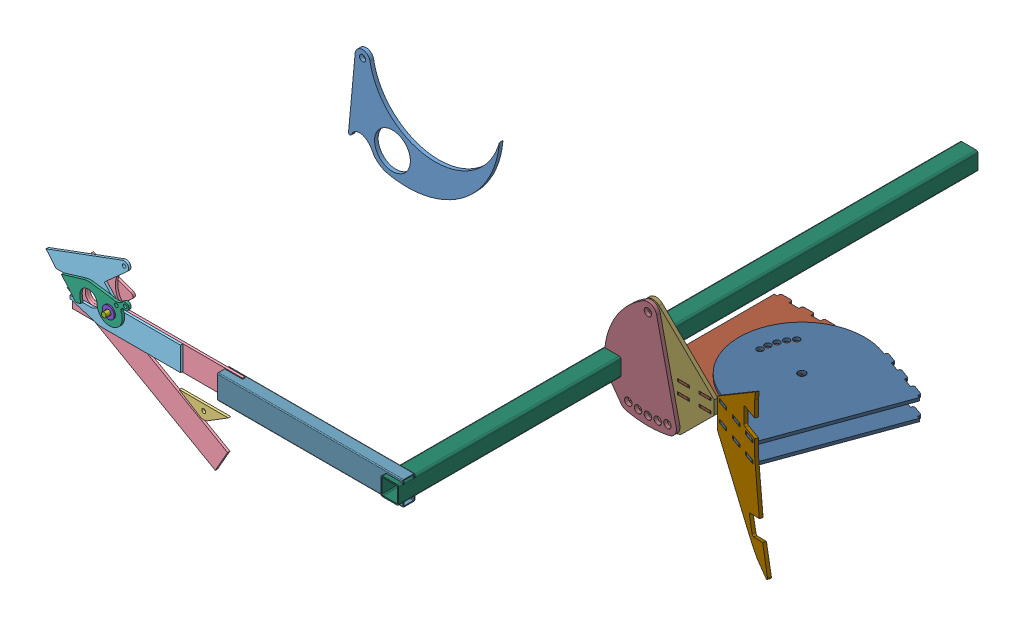
SolidWorks assembly Механизм подъема, configuration 00. Lengths in mm.
Overall size (2570.87 437.97 1423.53).
125 component instances, 32 part files, 102 mates.
Components (placement in the parent):
- Вилка-1: Вилка [--] at (-100 153.8415 0) size (225.09 67 8) (hidden)
- Собачка-1: Собачка [--] at (-64.5 153.8415 -8) size (115.18 50.5 4) (hidden)
- ТП.016.03.05.01 - Ложемент бок (4мм)-1: ТП.016.03.05.01 - Ложемент бок (4мм) [--] at (-100 153.8415 -12) size (285 93.38 4) (hidden)
- ТП.016.03.05.02 - Ложемент низ (4мм)-1: ТП.016.03.05.02 - Ложемент низ (4мм) [--] at (150 118.8415 -16) size (285 4 44) (hidden)
- ТП.016.03.06.01 - Труба связка-1: ТП.016.03.06.01 - Труба связка [--] at (-100 114.8415 28) size (21.3 21.3 971.2) (hidden)
- Модель подъема-1: Модель подъема [--] at (-100 178.8415 -441.6) size (479.74 429.14 0) (hidden)
- ТП.016.03.01.01 - Зуб подъемника (6мм)-1: ТП.016.03.01.01 - Зуб подъемника (6мм) [--] at (-45 169.6674 -441.6) x (0.869959 0.493123 0) z (0 0 1) size (274.94 199.54 6)
- Подшипник ГОСТ 8338-75 -2: Подшипник ГОСТ 8338-75  [Подшипник 205 ГОСТ 8338-75] at (-45 169.6674 -449.1) x (0 0 1) z (-0.017314 -0.99985 0) size (15 52 52) (hidden)
- ТП.016.03.01.02 - Ступица подъема-1: ТП.016.03.01.02 - Ступица подъема [--] at (-45 169.6674 -461.6) x (-1 0 0) z (0 0 -1) size (60 60 40) (hidden)
- ТП.016.03.02 - Ось подъема-1: ТП.016.03.02 - Ось подъема [--] at (-45 169.6674 -461.6) x (-1 0 0) z (0 0 -1) size (25 25 86) (hidden)
- ТП.016.03.03 - Стакан оси подъема-1: ТП.016.03.03 - Стакан оси подъема [--] at (-45 169.6674 -441.6) size (40 40 28) (hidden)
- ТП.016.03.03 - Стакан оси подъема-2: ТП.016.03.03 - Стакан оси подъема [--] at (-45 169.6674 -481.6) x (-1 0 0) z (0 0 -1) size (40 40 28) (hidden)
- ТП.016.03.01.01 - Зуб подъемника (6мм)-2: ТП.016.03.01.01 - Зуб подъемника (6мм) [--] at (-45 169.6674 -475.6) x (0.869959 0.493123 0) z (0 0 1) size (274.94 199.54 6) (hidden)
- Подшипник ГОСТ 8338-75 -3: Подшипник ГОСТ 8338-75  [Подшипник 205 ГОСТ 8338-75] at (-45 169.6674 -474.1) x (0 0 -1) z (0.017314 0.99985 0) size (15 52 52) (hidden)
- ТП.016.03.05.03 - Хомут связки (4мм)-1: ТП.016.03.05.03 - Хомут связки (4мм) [--] at (150 114.8415 -16) size (82.5 38.3 4)
- ТП.016.03.05.04 - Шайба связки (4мм)-1: ТП.016.03.05.04 - Шайба связки (4мм) [--] at (150 114.8415 28) size (82.5 23.3 4)
- ТП.016.03.05.01(01) - Ложемент бок (4мм)-1: ТП.016.03.05.01(01) - Ложемент бок (4мм) [--] at (-100 153.8415 4) size (285 93.13 4)
- ТП.016.03.05.01(01) - Ложемент бок (4мм)-2: ТП.016.03.05.01(01) - Ложемент бок (4мм) [--] at (-100 153.8415 0) x (0.869683 -0.49361 0) z (0 0 1) size (285 93.13 4)
- ТП.016.10.01.01.02.02.01 - Вилка навески (Ст3 S4мм)-1: ТП.016.10.01.01.02.02.01 - Вилка навески (Ст3 S4мм) [ЛАЗЕР] at (-100 153.8415 4) size (225.09 114.93 4)
- ТП.016.10.03.01 - Собачка навески (Ст3 S-4мм)-1: ТП.016.10.03.01 - Собачка навески (Ст3 S-4мм) [На лазер] at (-64.5 153.8415 8) size (112.78 47.58 4)
- ТП.016.10.01.01.02.02.02 - Ось вилки навески-1: ТП.016.10.01.01.02.02.02 - Ось вилки навески [--] at (-64.5 153.8415 4) size (12 12 18)
- ТП.016.10.02 - Втулка собачки навески-1: ТП.016.10.02 - Втулка собачки навески [--] at (-64.5 153.8415 12) size (20 20 6.5)
- ТП.016.11.02.00 - Отвал в сборе-1: ТП.016.11.02.00 - Отвал в сборе [00] at (826.1753 189.0389 -461.6) size (277.03 437.97 1410) (hidden)
  - ТП.016.11.02.01 - Полотно отвала (Ст3 S-2мм)-1: ТП.016.11.02.01 - Полотно отвала (Ст3 S-2мм) [--] at origin size (68.17 399.04 1400)
  - ТП.016.11.02.02 - Продольная труба-1: ТП.016.11.02.02 - Продольная труба [--] at origin size (30 30 1400)
  - ТП.016.11.02.02 - Продольная труба-2: ТП.016.11.02.02 - Продольная труба [--] at (-7.8024 -145.4172 0) x (-0.951057 -0.309017 0) z (0 0 1) size (30 30 1400)
  - ТП.016.11.02.03 - Ребро жесткости отвала (Ст3 S-2мм)-1: ТП.016.11.02.03 - Ребро жесткости отвала (Ст3 S-2мм) [--] at (0 0 675) size (117.05 393.58 2)
  - ТП.016.11.02.03 - Ребро жесткости отвала (Ст3 S-2мм)-2: ТП.016.11.02.03 - Ребро жесткости отвала (Ст3 S-2мм) [--] at (0 0 373) size (117.05 393.58 2)
  - ТП.016.11.02.03 - Ребро жесткости отвала (Ст3 S-2мм)-3: ТП.016.11.02.03 - Ребро жесткости отвала (Ст3 S-2мм) [--] at (0 0 -371) size (117.05 393.58 2)
  - ТП.016.11.02.03 - Ребро жесткости отвала (Ст3 S-2мм)-4: ТП.016.11.02.03 - Ребро жесткости отвала (Ст3 S-2мм) [--] at (0 0 -673) size (117.05 393.58 2)
  - ТП.016.11.02.04.00 - Кронштейн силовой-1: ТП.016.11.02.04.00 - Кронштейн силовой [00] at (-102.2517 -49.6474 0) size (244.94 251.23 220)
    - ТП.016.11.02.04.01 - Цапфа отвала (Ст3 S-5мм)-1: ТП.016.11.02.04.01 - Цапфа отвала (Ст3 S-5мм) [--] at origin size (208.66 5 220)
    - ТП.016.11.02.04.02 - Ребро силовое (Ст3 S-5мм)-1: ТП.016.11.02.04.02 - Ребро силовое (Ст3 S-5мм) [--] at (105.2 0.2 105) size (139.74 251.23 5)
    - ТП.016.11.02.04.02 - Ребро силовое (Ст3 S-5мм)-2: ТП.016.11.02.04.02 - Ребро силовое (Ст3 S-5мм) [--] at (105.2 0.2 -110) size (139.74 251.23 5)
    - ТП.016.11.02.04.01 - Цапфа отвала (Ст3 S-5мм)-2: ТП.016.11.02.04.01 - Цапфа отвала (Ст3 S-5мм) [--] at (0 25.4 0) x (1 0 0) z (0 0 -1) size (208.66 5 220)
  - ТП.016.11.02.05 - Юбка-1: ТП.016.11.02.05 - Юбка [--] at (37.9014 -187.7385 0) x (0.309017 -0.951057 0) z (0 0 1) size (85 8 1410)
  - Болты с шестигранной головкой кт.В (ГОСТ 7798-70)-1: Болты с шестигранной головкой кт.В (ГОСТ 7798-70) [Болт М6-6gx20(S10) ГОСТ 7798-77] at (42.4178 -175.75 690) x (-0.951057 -0.309017 0) z (-0.032305 0.099423 -0.994521) size (24 10.9 10)
  - Шайбы (ГОСТ 11371-78)-1: Шайбы (ГОСТ 11371-78) [Шайба 6 ГОСТ 11371-78] at (32.1464 -179.0874 690) x (0.951057 0.309017 0) z (0.304733 -0.937871 -0.165941) size (1.6 12 12)
  - Гайка (ГОСТ ISO 4032-2014)-1: Гайка (ГОСТ ISO 4032-2014) [Гайка М6 (ГОСТ ISO 4032)] at (28.9128 -180.1381 690) x (0.080366 -0.247341 0.96559) z (0.951057 0.309017 0) size (10 11.05 5.2)
  - Гайка (ГОСТ ISO 4032-2014)-2: Гайка (ГОСТ ISO 4032-2014) [Гайка М6 (ГОСТ ISO 4032)] at (28.9128 -180.1381 552) x (0.14073 -0.433124 0.89028) z (0.951057 0.309017 0) size (10 11.05 5.2)
  - Болты с шестигранной головкой кт.В (ГОСТ 7798-70)-2: Болты с шестигранной головкой кт.В (ГОСТ 7798-70) [Болт М6-6gx20(S10) ГОСТ 7798-77] at (42.4178 -175.75 552) x (-0.951057 -0.309017 0) z (-0.095584 0.294177 -0.950959) size (24 10.9 10)
  - Шайбы (ГОСТ 11371-78)-2: Шайбы (ГОСТ 11371-78) [Шайба 6 ГОСТ 11371-78] at (32.1464 -179.0874 552) x (0.951057 0.309017 0) z (0.287378 -0.884458 -0.367626) size (1.6 12 12)
  - Гайка (ГОСТ ISO 4032-2014)-3: Гайка (ГОСТ ISO 4032-2014) [Гайка М6 (ГОСТ ISO 4032)] at (28.9128 -180.1381 414) x (0.189473 -0.583138 0.789968) z (0.951057 0.309017 0) size (10 11.05 5.2)
  - Болты с шестигранной головкой кт.В (ГОСТ 7798-70)-3: Болты с шестигранной головкой кт.В (ГОСТ 7798-70) [Болт М6-6gx20(S10) ГОСТ 7798-77] at (42.4178 -175.75 414) x (-0.951057 -0.309017 0) z (-0.148605 0.45736 -0.876777) size (24 10.9 10)
  - Шайбы (ГОСТ 11371-78)-3: Шайбы (ГОСТ 11371-78) [Шайба 6 ГОСТ 11371-78] at (32.1464 -179.0874 414) x (0.951057 0.309017 0) z (0.261214 -0.803934 -0.534282) size (1.6 12 12)
  - Гайка (ГОСТ ISO 4032-2014)-4: Гайка (ГОСТ ISO 4032-2014) [Гайка М6 (ГОСТ ISO 4032)] at (28.9128 -180.1381 276) x (0.225997 -0.695549 0.68201) z (0.951057 0.309017 0) size (10 11.05 5.2)
  - Болты с шестигранной головкой кт.В (ГОСТ 7798-70)-4: Болты с шестигранной головкой кт.В (ГОСТ 7798-70) [Болт М6-6gx20(S10) ГОСТ 7798-77] at (42.4178 -175.75 276) x (-0.951057 -0.309017 0) z (-0.189933 0.584555 -0.78881) size (24 10.9 10)
  - Шайбы (ГОСТ 11371-78)-4: Шайбы (ГОСТ 11371-78) [Шайба 6 ГОСТ 11371-78] at (32.1464 -179.0874 276) x (0.951057 0.309017 0) z (0.231523 -0.712554 -0.662318) size (1.6 12 12)
  - Гайка (ГОСТ ISO 4032-2014)-5: Гайка (ГОСТ ISO 4032-2014) [Гайка М6 (ГОСТ ISO 4032)] at (28.9128 -180.1381 138) x (0.250965 -0.77239 0.583464) z (0.951057 0.309017 0) size (10 11.05 5.2)
  - Болты с шестигранной головкой кт.В (ГОСТ 7798-70)-5: Болты с шестигранной головкой кт.В (ГОСТ 7798-70) [Болт М6-6gx20(S10) ГОСТ 7798-77] at (42.4178 -175.75 138) x (-0.951057 -0.309017 0) z (-0.219391 0.675215 -0.704239) size (24 10.9 10)
  - Шайбы (ГОСТ 11371-78)-5: Шайбы (ГОСТ 11371-78) [Шайба 6 ГОСТ 11371-78] at (32.1464 -179.0874 138) x (0.951057 0.309017 0) z (0.203614 -0.626661 -0.752222) size (1.6 12 12)
  - Гайка (ГОСТ ISO 4032-2014)-6: Гайка (ГОСТ ISO 4032-2014) [Гайка М6 (ГОСТ ISO 4032)] at (28.9128 -180.1381 0) x (0.265821 -0.818113 0.509932) z (0.951057 0.309017 0) size (10 11.05 5.2)
  - Болты с шестигранной головкой кт.В (ГОСТ 7798-70)-6: Болты с шестигранной головкой кт.В (ГОСТ 7798-70) [Болт М6-6gx20(S10) ГОСТ 7798-77] at (42.4178 -175.75 0) x (-0.951057 -0.309017 0) z (-0.237644 0.731394 -0.639209) size (24 10.9 10)
  - Шайбы (ГОСТ 11371-78)-6: Шайбы (ГОСТ 11371-78) [Шайба 6 ГОСТ 11371-78] at (32.1464 -179.0874 0) x (0.951057 0.309017 0) z (0.182427 -0.561452 -0.80715) size (1.6 12 12)
  - Гайка (ГОСТ ISO 4032-2014)-7: Гайка (ГОСТ ISO 4032-2014) [Гайка М6 (ГОСТ ISO 4032)] at (28.9128 -180.1381 -138) x (0.272004 -0.837142 0.474559) z (0.951057 0.309017 0) size (10 11.05 5.2)
  - Болты с шестигранной головкой кт.В (ГОСТ 7798-70)-7: Болты с шестигранной головкой кт.В (ГОСТ 7798-70) [Болт М6-6gx20(S10) ГОСТ 7798-77] at (42.4178 -175.75 -138) x (-0.951057 -0.309017 0) z (-0.245474 0.755491 -0.607434) size (24 10.9 10)
  - Шайбы (ГОСТ 11371-78)-7: Шайбы (ГОСТ 11371-78) [Шайба 6 ГОСТ 11371-78] at (32.1464 -179.0874 -138) x (0.951057 0.309017 0) z (0.172142 -0.529798 -0.830471) size (1.6 12 12)
  - Гайка (ГОСТ ISO 4032-2014)-8: Гайка (ГОСТ ISO 4032-2014) [Гайка М6 (ГОСТ ISO 4032)] at (28.9128 -180.1381 -276) x (0.26996 -0.830852 0.486627) z (0.951057 0.309017 0) size (10 11.05 5.2)
  - Болты с шестигранной головкой кт.В (ГОСТ 7798-70)-8: Болты с шестигранной головкой кт.В (ГОСТ 7798-70) [Болт М6-6gx20(S10) ГОСТ 7798-77] at (42.4178 -175.75 -276) x (-0.951057 -0.309017 0) z (-0.242868 0.74747 -0.618307) size (24 10.9 10)
  - Шайбы (ГОСТ 11371-78)-8: Шайбы (ГОСТ 11371-78) [Шайба 6 ГОСТ 11371-78] at (32.1464 -179.0874 -276) x (0.951057 0.309017 0) z (0.175657 -0.540616 -0.822726) size (1.6 12 12)
  - Гайка (ГОСТ ISO 4032-2014)-9: Гайка (ГОСТ ISO 4032-2014) [Гайка М6 (ГОСТ ISO 4032)] at (28.9128 -180.1381 -414) x (0.258386 -0.79523 0.548494) z (0.951057 0.309017 0) size (10 11.05 5.2)
  - Болты с шестигранной головкой кт.В (ГОСТ 7798-70)-9: Болты с шестигранной головкой кт.В (ГОСТ 7798-70) [Болт М6-6gx20(S10) ГОСТ 7798-77] at (42.4178 -175.75 -414) x (-0.951057 -0.309017 0) z (-0.228423 0.703014 -0.673493) size (24 10.9 10)
  - Шайбы (ГОСТ 11371-78)-9: Шайбы (ГОСТ 11371-78) [Шайба 6 ГОСТ 11371-78] at (32.1464 -179.0874 -414) x (0.951057 0.309017 0) z (0.193572 -0.595754 -0.779491) size (1.6 12 12)
  - Гайка (ГОСТ ISO 4032-2014)-10: Гайка (ГОСТ ISO 4032-2014) [Гайка М6 (ГОСТ ISO 4032)] at (28.9128 -180.1381 -552) x (0.234692 -0.722307 0.650532) z (0.951057 0.309017 0) size (10 11.05 5.2)
  - Болты с шестигранной головкой кт.В (ГОСТ 7798-70)-10: Болты с шестигранной головкой кт.В (ГОСТ 7798-70) [Болт М6-6gx20(S10) ГОСТ 7798-77] at (42.4178 -175.75 -552) x (-0.951057 -0.309017 0) z (-0.200053 0.6157 -0.762163) size (24 10.9 10)
  - Шайбы (ГОСТ 11371-78)-10: Шайбы (ГОСТ 11371-78) [Шайба 6 ГОСТ 11371-78] at (32.1464 -179.0874 -552) x (0.951057 0.309017 0) z (0.222677 -0.685331 -0.693352) size (1.6 12 12)
  - Гайка (ГОСТ ISO 4032-2014)-11: Гайка (ГОСТ ISO 4032-2014) [Гайка М6 (ГОСТ ISO 4032)] at (28.9128 -180.1381 -690) x (0.197744 -0.608594 0.768447) z (0.951057 0.309017 0) size (10 11.05 5.2)
  - Болты с шестигранной головкой кт.В (ГОСТ 7798-70)-11: Болты с шестигранной головкой кт.В (ГОСТ 7798-70) [Болт М6-6gx20(S10) ГОСТ 7798-77] at (42.4178 -175.75 -690) x (-0.951057 -0.309017 0) z (-0.157821 0.485724 -0.859747) size (24 10.9 10)
  - Шайбы (ГОСТ 11371-78)-11: Шайбы (ГОСТ 11371-78) [Шайба 6 ГОСТ 11371-78] at (32.1464 -179.0874 -690) x (0.951057 0.309017 0) z (0.25539 -0.786011 -0.562994) size (1.6 12 12)
- ТП.016.11.02.00 - Отвал в сборе-2: ТП.016.11.02.00 - Отвал в сборе [00] at (715.8804 189.0389 -426.6963) x (0.939693 0 0.34202) z (-0.34202 0 0.939693) size (277.03 437.97 1410) (hidden)
  - ТП.016.11.02.01 - Полотно отвала (Ст3 S-2мм)-1: ТП.016.11.02.01 - Полотно отвала (Ст3 S-2мм) [--] at origin size (68.17 399.04 1400)
  - ТП.016.11.02.02 - Продольная труба-1: ТП.016.11.02.02 - Продольная труба [--] at origin size (30 30 1400)
  - ТП.016.11.02.02 - Продольная труба-2: ТП.016.11.02.02 - Продольная труба [--] at (-7.8024 -145.4172 0) x (-0.951057 -0.309017 0) z (0 0 1) size (30 30 1400)
  - ТП.016.11.02.03 - Ребро жесткости отвала (Ст3 S-2мм)-1: ТП.016.11.02.03 - Ребро жесткости отвала (Ст3 S-2мм) [--] at (0 0 675) size (117.05 393.58 2)
  - ТП.016.11.02.03 - Ребро жесткости отвала (Ст3 S-2мм)-2: ТП.016.11.02.03 - Ребро жесткости отвала (Ст3 S-2мм) [--] at (0 0 373) size (117.05 393.58 2)
  - ТП.016.11.02.03 - Ребро жесткости отвала (Ст3 S-2мм)-3: ТП.016.11.02.03 - Ребро жесткости отвала (Ст3 S-2мм) [--] at (0 0 -371) size (117.05 393.58 2)
  - ТП.016.11.02.03 - Ребро жесткости отвала (Ст3 S-2мм)-4: ТП.016.11.02.03 - Ребро жесткости отвала (Ст3 S-2мм) [--] at (0 0 -673) size (117.05 393.58 2)
  - ТП.016.11.02.04.00 - Кронштейн силовой-1: ТП.016.11.02.04.00 - Кронштейн силовой [00] at (-102.2517 -49.6474 0) size (244.94 251.23 220)
    - ТП.016.11.02.04.01 - Цапфа отвала (Ст3 S-5мм)-1: ТП.016.11.02.04.01 - Цапфа отвала (Ст3 S-5мм) [--] at origin size (208.66 5 220)
    - ТП.016.11.02.04.02 - Ребро силовое (Ст3 S-5мм)-1: ТП.016.11.02.04.02 - Ребро силовое (Ст3 S-5мм) [--] at (105.2 0.2 105) size (139.74 251.23 5)
    - ТП.016.11.02.04.02 - Ребро силовое (Ст3 S-5мм)-2: ТП.016.11.02.04.02 - Ребро силовое (Ст3 S-5мм) [--] at (105.2 0.2 -110) size (139.74 251.23 5)
    - ТП.016.11.02.04.01 - Цапфа отвала (Ст3 S-5мм)-2: ТП.016.11.02.04.01 - Цапфа отвала (Ст3 S-5мм) [--] at (0 25.4 0) x (1 0 0) z (0 0 -1) size (208.66 5 220)
  - ТП.016.11.02.05 - Юбка-1: ТП.016.11.02.05 - Юбка [--] at (37.9014 -187.7385 0) x (0.309017 -0.951057 0) z (0 0 1) size (85 8 1410)
  - Болты с шестигранной головкой кт.В (ГОСТ 7798-70)-1: Болты с шестигранной головкой кт.В (ГОСТ 7798-70) [Болт М6-6gx20(S10) ГОСТ 7798-77] at (42.4178 -175.75 690) x (-0.951057 -0.309017 0) z (-0.032305 0.099423 -0.994521) size (24 10.9 10)
  - Шайбы (ГОСТ 11371-78)-1: Шайбы (ГОСТ 11371-78) [Шайба 6 ГОСТ 11371-78] at (32.1464 -179.0874 690) x (0.951057 0.309017 0) z (0.304733 -0.937871 -0.165941) size (1.6 12 12)
  - Гайка (ГОСТ ISO 4032-2014)-1: Гайка (ГОСТ ISO 4032-2014) [Гайка М6 (ГОСТ ISO 4032)] at (28.9128 -180.1381 690) x (0.080366 -0.247341 0.96559) z (0.951057 0.309017 0) size (10 11.05 5.2)
  - Гайка (ГОСТ ISO 4032-2014)-2: Гайка (ГОСТ ISO 4032-2014) [Гайка М6 (ГОСТ ISO 4032)] at (28.9128 -180.1381 552) x (0.14073 -0.433124 0.89028) z (0.951057 0.309017 0) size (10 11.05 5.2)
  - Болты с шестигранной головкой кт.В (ГОСТ 7798-70)-2: Болты с шестигранной головкой кт.В (ГОСТ 7798-70) [Болт М6-6gx20(S10) ГОСТ 7798-77] at (42.4178 -175.75 552) x (-0.951057 -0.309017 0) z (-0.095584 0.294177 -0.950959) size (24 10.9 10)
  - Шайбы (ГОСТ 11371-78)-2: Шайбы (ГОСТ 11371-78) [Шайба 6 ГОСТ 11371-78] at (32.1464 -179.0874 552) x (0.951057 0.309017 0) z (0.287378 -0.884458 -0.367626) size (1.6 12 12)
  - Гайка (ГОСТ ISO 4032-2014)-3: Гайка (ГОСТ ISO 4032-2014) [Гайка М6 (ГОСТ ISO 4032)] at (28.9128 -180.1381 414) x (0.189473 -0.583138 0.789968) z (0.951057 0.309017 0) size (10 11.05 5.2)
  - Болты с шестигранной головкой кт.В (ГОСТ 7798-70)-3: Болты с шестигранной головкой кт.В (ГОСТ 7798-70) [Болт М6-6gx20(S10) ГОСТ 7798-77] at (42.4178 -175.75 414) x (-0.951057 -0.309017 0) z (-0.148605 0.45736 -0.876777) size (24 10.9 10)
  - Шайбы (ГОСТ 11371-78)-3: Шайбы (ГОСТ 11371-78) [Шайба 6 ГОСТ 11371-78] at (32.1464 -179.0874 414) x (0.951057 0.309017 0) z (0.261214 -0.803934 -0.534282) size (1.6 12 12)
  - Гайка (ГОСТ ISO 4032-2014)-4: Гайка (ГОСТ ISO 4032-2014) [Гайка М6 (ГОСТ ISO 4032)] at (28.9128 -180.1381 276) x (0.225997 -0.695549 0.68201) z (0.951057 0.309017 0) size (10 11.05 5.2)
  - Болты с шестигранной головкой кт.В (ГОСТ 7798-70)-4: Болты с шестигранной головкой кт.В (ГОСТ 7798-70) [Болт М6-6gx20(S10) ГОСТ 7798-77] at (42.4178 -175.75 276) x (-0.951057 -0.309017 0) z (-0.189933 0.584555 -0.78881) size (24 10.9 10)
  - Шайбы (ГОСТ 11371-78)-4: Шайбы (ГОСТ 11371-78) [Шайба 6 ГОСТ 11371-78] at (32.1464 -179.0874 276) x (0.951057 0.309017 0) z (0.231523 -0.712554 -0.662318) size (1.6 12 12)
  - Гайка (ГОСТ ISO 4032-2014)-5: Гайка (ГОСТ ISO 4032-2014) [Гайка М6 (ГОСТ ISO 4032)] at (28.9128 -180.1381 138) x (0.250965 -0.77239 0.583464) z (0.951057 0.309017 0) size (10 11.05 5.2)
  - Болты с шестигранной головкой кт.В (ГОСТ 7798-70)-5: Болты с шестигранной головкой кт.В (ГОСТ 7798-70) [Болт М6-6gx20(S10) ГОСТ 7798-77] at (42.4178 -175.75 138) x (-0.951057 -0.309017 0) z (-0.219391 0.675215 -0.704239) size (24 10.9 10)
  - Шайбы (ГОСТ 11371-78)-5: Шайбы (ГОСТ 11371-78) [Шайба 6 ГОСТ 11371-78] at (32.1464 -179.0874 138) x (0.951057 0.309017 0) z (0.203614 -0.626661 -0.752222) size (1.6 12 12)
  - Гайка (ГОСТ ISO 4032-2014)-6: Гайка (ГОСТ ISO 4032-2014) [Гайка М6 (ГОСТ ISO 4032)] at (28.9128 -180.1381 0) x (0.265821 -0.818113 0.509932) z (0.951057 0.309017 0) size (10 11.05 5.2)
  - Болты с шестигранной головкой кт.В (ГОСТ 7798-70)-6: Болты с шестигранной головкой кт.В (ГОСТ 7798-70) [Болт М6-6gx20(S10) ГОСТ 7798-77] at (42.4178 -175.75 0) x (-0.951057 -0.309017 0) z (-0.237644 0.731394 -0.639209) size (24 10.9 10)
  - Шайбы (ГОСТ 11371-78)-6: Шайбы (ГОСТ 11371-78) [Шайба 6 ГОСТ 11371-78] at (32.1464 -179.0874 0) x (0.951057 0.309017 0) z (0.182427 -0.561452 -0.80715) size (1.6 12 12)
  - Гайка (ГОСТ ISO 4032-2014)-7: Гайка (ГОСТ ISO 4032-2014) [Гайка М6 (ГОСТ ISO 4032)] at (28.9128 -180.1381 -138) x (0.272004 -0.837142 0.474559) z (0.951057 0.309017 0) size (10 11.05 5.2)
  - Болты с шестигранной головкой кт.В (ГОСТ 7798-70)-7: Болты с шестигранной головкой кт.В (ГОСТ 7798-70) [Болт М6-6gx20(S10) ГОСТ 7798-77] at (42.4178 -175.75 -138) x (-0.951057 -0.309017 0) z (-0.245474 0.755491 -0.607434) size (24 10.9 10)
  - Шайбы (ГОСТ 11371-78)-7: Шайбы (ГОСТ 11371-78) [Шайба 6 ГОСТ 11371-78] at (32.1464 -179.0874 -138) x (0.951057 0.309017 0) z (0.172142 -0.529798 -0.830471) size (1.6 12 12)
  - Гайка (ГОСТ ISO 4032-2014)-8: Гайка (ГОСТ ISO 4032-2014) [Гайка М6 (ГОСТ ISO 4032)] at (28.9128 -180.1381 -276) x (0.26996 -0.830852 0.486627) z (0.951057 0.309017 0) size (10 11.05 5.2)
  - Болты с шестигранной головкой кт.В (ГОСТ 7798-70)-8: Болты с шестигранной головкой кт.В (ГОСТ 7798-70) [Болт М6-6gx20(S10) ГОСТ 7798-77] at (42.4178 -175.75 -276) x (-0.951057 -0.309017 0) z (-0.242868 0.74747 -0.618307) size (24 10.9 10)
  - Шайбы (ГОСТ 11371-78)-8: Шайбы (ГОСТ 11371-78) [Шайба 6 ГОСТ 11371-78] at (32.1464 -179.0874 -276) x (0.951057 0.309017 0) z (0.175657 -0.540616 -0.822726) size (1.6 12 12)
  - Гайка (ГОСТ ISO 4032-2014)-9: Гайка (ГОСТ ISO 4032-2014) [Гайка М6 (ГОСТ ISO 4032)] at (28.9128 -180.1381 -414) x (0.258386 -0.79523 0.548494) z (0.951057 0.309017 0) size (10 11.05 5.2)
  - Болты с шестигранной головкой кт.В (ГОСТ 7798-70)-9: Болты с шестигранной головкой кт.В (ГОСТ 7798-70) [Болт М6-6gx20(S10) ГОСТ 7798-77] at (42.4178 -175.75 -414) x (-0.951057 -0.309017 0) z (-0.228423 0.703014 -0.673493) size (24 10.9 10)
  - Шайбы (ГОСТ 11371-78)-9: Шайбы (ГОСТ 11371-78) [Шайба 6 ГОСТ 11371-78] at (32.1464 -179.0874 -414) x (0.951057 0.309017 0) z (0.193572 -0.595754 -0.779491) size (1.6 12 12)
  - Гайка (ГОСТ ISO 4032-2014)-10: Гайка (ГОСТ ISO 4032-2014) [Гайка М6 (ГОСТ ISO 4032)] at (28.9128 -180.1381 -552) x (0.234692 -0.722307 0.650532) z (0.951057 0.309017 0) size (10 11.05 5.2)
  - Болты с шестигранной головкой кт.В (ГОСТ 7798-70)-10: Болты с шестигранной головкой кт.В (ГОСТ 7798-70) [Болт М6-6gx20(S10) ГОСТ 7798-77] at (42.4178 -175.75 -552) x (-0.951057 -0.309017 0) z (-0.200053 0.6157 -0.762163) size (24 10.9 10)
  - Шайбы (ГОСТ 11371-78)-10: Шайбы (ГОСТ 11371-78) [Шайба 6 ГОСТ 11371-78] at (32.1464 -179.0874 -552) x (0.951057 0.309017 0) z (0.222677 -0.685331 -0.693352) size (1.6 12 12)
  - Гайка (ГОСТ ISO 4032-2014)-11: Гайка (ГОСТ ISO 4032-2014) [Гайка М6 (ГОСТ ISO 4032)] at (28.9128 -180.1381 -690) x (0.197744 -0.608594 0.768447) z (0.951057 0.309017 0) size (10 11.05 5.2)
  - Болты с шестигранной головкой кт.В (ГОСТ 7798-70)-11: Болты с шестигранной головкой кт.В (ГОСТ 7798-70) [Болт М6-6gx20(S10) ГОСТ 7798-77] at (42.4178 -175.75 -690) x (-0.951057 -0.309017 0) z (-0.157821 0.485724 -0.859747) size (24 10.9 10)
  - Шайбы (ГОСТ 11371-78)-11: Шайбы (ГОСТ 11371-78) [Шайба 6 ГОСТ 11371-78] at (32.1464 -179.0874 -690) x (0.951057 0.309017 0) z (0.25539 -0.786011 -0.562994) size (1.6 12 12)
- ТП.016.11.02.04.02 - Ребро силовое (Ст3 S-5мм)-1: ТП.016.11.02.04.02 - Ребро силовое (Ст3 S-5мм) [--] at (682.7388 139.5915 -327.0202) x (0.939693 0 0.34202) z (-0.34202 0 0.939693) size (139.74 251.23 5)
- ТП.016.11.02.04.01 - Цапфа отвала (Ст3 S-5мм)-1: ТП.016.11.02.04.01 - Цапфа отвала (Ст3 S-5мм) [--] at (619.9831 139.5915 -461.6) x (0.939693 0 0.34202) z (-0.34202 0 0.939693) size (208.66 5 220)
- ТП.016.11.01.01.01 - Цапфа навески (Ст3 S-4мм)-1: ТП.016.11.01.01.01 - Цапфа навески (Ст3 S-4мм) [--] at (619.9831 139.5915 -461.6) size (200 4 209.34)
- ТП.016.11.01.02 - Кронштейн навески (Ст3 S-6мм)-1: ТП.016.11.01.02 - Кронштейн навески (Ст3 S-6мм) [--] at (577.703 139.5915 -362.9323) x (-1 0 0) z (0 0 1) size (156.54 180 6)
- ТП.016.11.01.01.01 - Цапфа навески (Ст3 S-4мм)-2: ТП.016.11.01.01.01 - Цапфа навески (Ст3 S-4мм) [--] at (619.9831 158.5915 -461.6) size (200 4 209.34)
- ТП.016.11.02.04.01 - Цапфа отвала (Ст3 S-5мм)-2: ТП.016.11.02.04.01 - Цапфа отвала (Ст3 S-5мм) [--] at (619.9831 169.5915 -461.6) x (0.939693 0 0.34202) z (-0.34202 0 0.939693) size (208.66 5 220)
- ТП.016.10.01.02 - Кронштейн рампы (Ст3 S-6мм)-1: ТП.016.10.01.02 - Кронштейн рампы (Ст3 S-6мм) [--] at (415 139.5915 -354.9323) size (119.68 179.72 6)
- ТП.016.10.01.01.02.01 - Боковина рампы-1: ТП.016.10.01.01.02.01 - Боковина рампы [--] at (400 118.8415 -4) x (0 0 -1) z (1 0 0) size (20 40 310)
- ТП.016.10.01.01.01 - Поперечина рампы-1: ТП.016.10.01.01.01 - Поперечина рампы [--] at (415 139.5915 -461.6) size (30 30 969.2)
Mates (geometry in assembly coordinates):
- Совпадение1: coincident: plane of Вилка-1 through (-100 153.8415 0) normal (0 0 1); plane of assembly through (0 0 0) normal (0 0 1)
- Совпадение2: coincident: plane of Вилка-1 through (-100 153.8415 0) normal (0 1 0); point of assembly
- Совпадение3: coincident: plane of Вилка-1 through (-100 153.8415 0) normal (1 0 0); point of assembly
- Параллельность1: parallel: plane of Вилка-1 through (-100 153.8415 0) normal (0 1 0); line of assembly
- Совпадение4: coincident: plane of Вилка-1 through (-100 153.8415 -8) normal (0 0 -1); plane of Собачка-1 through (-64.5 153.8415 -8) normal (0 0 1)
- Совпадение5: coincident: point of Вилка-1; plane of Собачка-1 through (-64.5 153.8415 -8) normal (0 1 0)
- Параллельность2: parallel: plane of Вилка-1 through (50 120.3415 -8) normal (0 -1 0); plane of Собачка-1 through (-64.5 153.8415 -8) normal (0 1 0)
- Совпадение6: coincident: plane of Собачка-1 through (-64.5 153.8415 -8) normal (1 0 0); point of assembly
- Совпадение7: coincident: plane of Собачка-1 through (-100 153.8415 -12) normal (0 0 -1); plane of ТП.016.03.05.01 - Ложемент бок (4мм)-1 through (-100 153.8415 -12) normal (0 0 1)
- Совпадение8: coincident: plane of ТП.016.03.05.01 - Ложемент бок (4мм)-1 through (-100 153.8415 -12) normal (0 1 0); point of assembly
- Совпадение9: coincident: plane of ТП.016.03.05.01 - Ложемент бок (4мм)-1 through (-100 153.8415 -12) normal (1 0 0); point of assembly
- Параллельность3: parallel: plane of Вилка-1 through (50 120.3415 -8) normal (0 -1 0); plane of ТП.016.03.05.01 - Ложемент бок (4мм)-1 through (-100 153.8415 -12) normal (0 1 0)
- Совпадение10: coincident: plane of ТП.016.03.05.01 - Ложемент бок (4мм)-1 through (-19.33 190.8761 -16) normal (0 0 -1); plane of ТП.016.03.05.02 - Ложемент низ (4мм)-1 through (150 118.8415 -16) normal (0 0 1)
- Совпадение11: coincident: plane of ТП.016.03.05.01 - Ложемент бок (4мм)-1 through (-100 118.8415 -16) normal (0 -1 0); plane of ТП.016.03.05.02 - Ложемент низ (4мм)-1 through (150 118.8415 -16) normal (0 1 0)
- Совпадение12: coincident: plane of ТП.016.03.05.01 - Ложемент бок (4мм)-1 through (150 118.8415 -16) normal (1 0 0); plane of ТП.016.03.05.02 - Ложемент низ (4мм)-1 through (150 118.8415 -16) normal (1 0 0)
- Совпадение13: coincident: plane of ТП.016.03.05.02 - Ложемент низ (4мм)-1 through (-135 114.8415 28) normal (0 0 1); plane of ТП.016.03.06.01 - Труба связка-1 through (-100 114.8415 28) normal (0 0 1)
- Совпадение14: coincident: plane of ТП.016.03.05.02 - Ложемент низ (4мм)-1 through (150 114.8415 -16) normal (0 -1 0); plane of ТП.016.03.06.01 - Труба связка-1 through (-100 114.8415 28) normal (0 1 0)
- Совпадение15: coincident: plane of ТП.016.03.06.01 - Труба связка-1 through (-100 114.8415 28) normal (1 0 0); point of assembly
- Совпадение16: coincident: plane of ? through (171.6828 47.7635 -200) normal (0 0 1); plane of assembly through (0 0 -200) normal (0 0 1)
- Совпадение17: coincident: plane of Модель подъема-1 through (-100 178.8415 -441.6) normal (0 0 1); plane of assembly through (0 0 -441.6) normal (0 0 1)
- Совпадение18: coincident: plane of Модель подъема-1 through (-100 178.8415 -441.6) normal (0 1 0); line of assembly
- Совпадение19: coincident: plane of Модель подъема-1 through (-100 178.8415 -441.6) normal (1 0 0); point of assembly
- Совпадение20: coincident: plane of ТП.016.03.01.01 - Зуб подъемника (6мм)-1 through (-45 169.6674 -441.6) normal (0 0 1); plane of assembly through (0 0 -441.6) normal (0 0 1)
- Совпадение21: coincident: point of Модель подъема-1; plane of ТП.016.03.01.01 - Зуб подъемника (6мм)-1 through (-45 169.6674 -441.6) normal (-0.493123 0.869959 0)
- Совпадение22: coincident: point of Модель подъема-1; plane of ТП.016.03.01.01 - Зуб подъемника (6мм)-1 through (-45 169.6674 -441.6) normal (-0.493123 0.869959 0)
- Совпадение23: coincident: point of Модель подъема-1; plane of ТП.016.03.01.01 - Зуб подъемника (6мм)-1 through (-45 169.6674 -441.6) normal (0.869959 0.493123 0)
- Совпадение24: coincident: plane of ТП.016.03.01.01 - Зуб подъемника (6мм)-1 through (-20.6077 284.0965 -441.6) normal (0 0 1); plane of Подшипник ГОСТ 8338-75 -2 through (-65.9969 170.031 -441.6) normal (0 0 1)
- Концентричный1: concentric: cylinder of ТП.016.03.01.01 - Зуб подъемника (6мм)-1 through (-45 169.6674 -447.6) axis (0 0 1) radius 30; cylinder of Подшипник ГОСТ 8338-75 -2 through (-45 169.6674 -1449.1) axis (0 0 -1) radius 26
- Совпадение25: coincident: plane of ТП.016.03.01.02 - Ступица подъема-1 through (-45 169.6674 -461.6) normal (0 0 -1); plane of assembly through (0 0 -461.6) normal (0 0 1)
- Совпадение26: coincident: point of Модель подъема-1; plane of ТП.016.03.01.02 - Ступица подъема-1 through (-45 169.6674 -461.6) normal (0 1 0)
- Параллельность4: parallel: plane of ТП.016.03.01.02 - Ступица подъема-1 through (-45 169.6674 -461.6) normal (0 1 0); plane of assembly through (0 0 0) normal (0 1 0)
- Совпадение27: coincident: point of Модель подъема-1; plane of ТП.016.03.01.02 - Ступица подъема-1 through (-45 169.6674 -461.6) normal (-1 0 0)
- Совпадение28: coordinate: point of ТП.016.03.01.02 - Ступица подъема-1; point of ТП.016.03.02 - Ось подъема-1
- Совпадение29: coincident: plane of Подшипник ГОСТ 8338-75 -2 through (-58.9979 169.9098 -441.6) normal (0 0 1); plane of ТП.016.03.03 - Стакан оси подъема-1 through (-45 169.6674 -441.6) normal (0 0 1)
- Совпадение30: coincident: plane of ТП.016.03.02 - Ось подъема-1 through (-45 169.6674 -461.6) normal (0 1 0); plane of ТП.016.03.03 - Стакан оси подъема-1 through (-45 169.6674 -441.6) normal (0 1 0)
- Совпадение31: coincident: plane of ТП.016.03.02 - Ось подъема-1 through (-45 169.6674 -461.6) normal (-1 0 0); plane of ТП.016.03.03 - Стакан оси подъема-1 through (-45 169.6674 -441.6) normal (1 0 0)
- Совпадение32: coincident: plane of ТП.016.03.05.01 - Ложемент бок (4мм)-1 through (-19.33 190.8761 -16) normal (0 0 -1); plane of ТП.016.03.05.03 - Хомут связки (4мм)-1 through (150 114.8415 -16) normal (0 0 1)
- Совпадение33: coincident: plane of ТП.016.03.05.02 - Ложемент низ (4мм)-1 through (150 114.8415 -16) normal (0 -1 0); plane of ТП.016.03.05.03 - Хомут связки (4мм)-1 through (150 114.8415 -16) normal (0 1 0)
- Совпадение34: coincident: plane of ТП.016.03.05.02 - Ложемент низ (4мм)-1 through (150 114.8415 28) normal (1 0 0); plane of ТП.016.03.05.03 - Хомут связки (4мм)-1 through (150 114.8415 -16) normal (1 0 0)
- Совпадение35: coincident: plane of ТП.016.03.05.02 - Ложемент низ (4мм)-1 through (-135 114.8415 28) normal (0 0 1); plane of ТП.016.03.05.04 - Шайба связки (4мм)-1 through (150 114.8415 28) normal (0 0 1)
- Совпадение36: coincident: plane of ТП.016.03.05.03 - Хомут связки (4мм)-1 through (150 114.8415 -16) normal (0 1 0); plane of ТП.016.03.05.04 - Шайба связки (4мм)-1 through (150 114.8415 28) normal (0 1 0)
- Совпадение37: coincident: plane of ТП.016.03.05.03 - Хомут связки (4мм)-1 through (150 114.8415 -16) normal (1 0 0); plane of ТП.016.03.05.04 - Шайба связки (4мм)-1 through (150 114.8415 28) normal (1 0 0)
- Совпадение38: coincident: plane of ? through (-24.6054 189.1519 0) normal (0 0 -1)
- Концентричный2: concentric: cylinder of ? through (-100 153.8415 0) axis (0 0 1) radius 13.5
- Параллельность5: parallel: plane of ? through (-100 118.8415 0) normal (0 -1 0)
- Совпадение39: coincident: plane of ТП.016.03.05.01(01) - Ложемент бок (4мм)-1 through (-24.6054 189.1519 0) normal (0 0 -1); plane of ТП.016.03.05.01(01) - Ложемент бок (4мм)-2 through (-17.001 147.3348 0) normal (0 0 1)
- Параллельность6: parallel: line of ТП.016.03.05.01(01) - Ложемент бок (4мм)-2 through (285 -147.7153 140.679) axis (0 0.869683 -0.49361); line of assembly
- Концентричный3: concentric: cylinder of ТП.016.03.05.01(01) - Ложемент бок (4мм)-1 through (-100 153.8415 0) axis (0 0 1) radius 13.5; cylinder of ТП.016.03.05.01(01) - Ложемент бок (4мм)-2 through (-100 153.8415 -4) axis (0 0 1) radius 13.5
- Совпадение40: coincident: plane of ТП.016.03.05.01(01) - Ложемент бок (4мм)-1 through (-24.6054 189.1519 4) normal (0 0 1); plane of ТП.016.10.01.01.02.02.01 - Вилка навески (Ст3 S4мм)-1 through (-100 153.8415 4) normal (0 0 1)
- Совпадение41: coincident: plane of ? through (-100 153.8415 4) normal (0 1 0)
- Совпадение42: coincident: plane of ? through (-100 153.8415 4) normal (1 0 0)
- Параллельность7: parallel: plane of ТП.016.03.05.01(01) - Ложемент бок (4мм)-1 through (-135 118.8415 0) normal (-1 0 0); plane of ТП.016.10.01.01.02.02.01 - Вилка навески (Ст3 S4мм)-1 through (-100 153.8415 4) normal (1 0 0)
- Совпадение43: coincident: plane of ТП.016.10.01.01.02.02.01 - Вилка навески (Ст3 S4мм)-1 through (-44.5 227.7764 8) normal (0 0 1); plane of ТП.016.10.03.01 - Собачка навески (Ст3 S-4мм)-1 through (-64.5 153.8415 8) normal (0 0 1)
- Совпадение44: coincident: plane of ТП.016.10.03.01 - Собачка навески (Ст3 S-4мм)-1 through (-64.5 153.8415 8) normal (0 1 0); point of assembly
- Совпадение45: coincident: plane of ТП.016.10.03.01 - Собачка навески (Ст3 S-4мм)-1 through (-64.5 153.8415 8) normal (1 0 0); point of assembly
- Параллельность8: parallel: plane of ТП.016.03.05.01(01) - Ложемент бок (4мм)-1 through (-135 118.8415 0) normal (-1 0 0); plane of ТП.016.10.03.01 - Собачка навески (Ст3 S-4мм)-1 through (-64.5 153.8415 8) normal (1 0 0)
- Совпадение46: coincident: plane of ТП.016.03.05.01(01) - Ложемент бок (4мм)-1 through (-24.6054 189.1519 4) normal (0 0 1); plane of ТП.016.10.01.01.02.02.02 - Ось вилки навески-1 through (-64.5 153.8415 4) normal (0 0 1)
- Совпадение48: coincident: plane of ТП.016.10.01.01.02.02.02 - Ось вилки навески-1 through (-64.5 153.8415 4) normal (1 0 0); point of assembly
- Совпадение49: coincident: plane of ТП.016.10.01.01.02.02.02 - Ось вилки навески-1 through (-64.5 153.8415 4) normal (0 1 0); point of assembly
- Параллельность9: parallel: plane of ТП.016.03.05.01(01) - Ложемент бок (4мм)-1 through (-135 118.8415 0) normal (-1 0 0); plane of ТП.016.10.01.01.02.02.02 - Ось вилки навески-1 through (-64.5 153.8415 4) normal (1 0 0)
- Совпадение50: coincident: plane of ТП.016.10.03.01 - Собачка навески (Ст3 S-4мм)-1 through (-100 153.8415 12) normal (0 0 1); plane of ТП.016.10.02 - Втулка собачки навески-1 through (-64.5 153.8415 12) normal (0 0 1)
- Совпадение51: coincident: plane of ТП.016.10.01.01.02.02.02 - Ось вилки навески-1 through (-64.5 153.8415 4) normal (0 1 0); point of assembly
- Совпадение52: coincident: plane of ТП.016.10.02 - Втулка собачки навески-1 through (-64.5 153.8415 12) normal (1 0 0); point of assembly
- Параллельность10: parallel: plane of ТП.016.03.05.01(01) - Ложемент бок (4мм)-1 through (-135 118.8415 0) normal (-1 0 0); plane of ТП.016.10.02 - Втулка собачки навески-1 through (-64.5 153.8415 12) normal (1 0 0)
- Совпадение53: coincident: plane of ТП.016.10.02 - Втулка собачки навески-1 through (-64.5 153.8415 12) normal (0 1 0); point of assembly
- Касательность1: tangent: cylinder of ? through (860.8665 -5 238.4) axis (0 0 -1) radius 5
- Параллельность11: parallel: plane of ? through (826.1753 189.0389 -461.6) normal (0 1 0); plane of assembly through (0 0 0) normal (0 1 0)
- Совпадение54: coincident: plane of ? through (826.1753 189.0389 -461.6) normal (0 0 1)
- Касательность2: tangent: cylinder of ? through (509.0654 -5 242.9537) axis (0.34202 0 -0.939693) radius 5
- Параллельность12: parallel: plane of ? through (715.8804 189.0389 -426.6963) normal (0 1 0); plane of assembly through (0 0 0) normal (0 1 0)
- Совпадение55: coincident: plane of ? through (477.9802 148.0342 231.6396) normal (-0.928123 -0.156434 -0.337809)
- Совпадение56: coincident: plane of ? through (715.8804 189.0389 -426.6963) normal (-0.34202 0 0.939693)
- Совпадение57: coincident: plane of ? through (682.7388 139.5915 -327.0202) normal (-0.34202 0 0.939693)
- Совпадение58: coincident: plane of ? through (682.7388 139.5915 -327.0202) normal (0 1 0)
- Совпадение59: coincident: plane of ? through (682.7388 139.5915 -327.0202) normal (0 1 0)
- Совпадение60: coincident: plane of ? through (682.7388 139.5915 -327.0202) normal (0.939693 0 0.34202)
- Совпадение61: coincident: plane of ТП.016.11.02.04.01 - Цапфа отвала (Ст3 S-5мм)-1 through (619.9831 139.5915 -461.6) normal (0 1 0); circle of assembly
- Совпадение62: coincident: plane of ТП.016.11.02.04.01 - Цапфа отвала (Ст3 S-5мм)-1 through (619.9831 139.5915 -461.6) normal (-0.34202 0 0.939693); line of assembly
- Совпадение63: coincident: plane of ТП.016.11.02.04.01 - Цапфа отвала (Ст3 S-5мм)-1 through (619.9831 139.5915 -461.6) normal (0.939693 0 0.34202); line of assembly
- Совпадение64: coincident: plane of ТП.016.11.02.04.01 - Цапфа отвала (Ст3 S-5мм)-1 through (619.9831 139.5915 -461.6) normal (0 1 0); plane of ТП.016.11.01.01.01 - Цапфа навески (Ст3 S-4мм)-1 through (619.9831 139.5915 -461.6) normal (0 1 0)
- Совпадение65: coincident: plane of ТП.016.11.01.01.01 - Цапфа навески (Ст3 S-4мм)-1 through (619.9831 139.5915 -461.6) normal (0 0 1); line of assembly
- Совпадение66: coincident: plane of ТП.016.11.01.01.01 - Цапфа навески (Ст3 S-4мм)-1 through (619.9831 139.5915 -461.6) normal (1 0 0); point of assembly
- Совпадение67: coincident: plane of ТП.016.11.01.01.01 - Цапфа навески (Ст3 S-4мм)-1 through (577.703 143.5915 -362.9323) normal (0 0 1); plane of ТП.016.11.01.02 - Кронштейн навески (Ст3 S-6мм)-1 through (577.703 139.5915 -362.9323) normal (0 0 1)
- Совпадение68: coincident: plane of ТП.016.11.01.01.01 - Цапфа навески (Ст3 S-4мм)-1 through (549.9831 139.5915 -461.6) normal (0 -1 0); plane of ТП.016.11.01.02 - Кронштейн навески (Ст3 S-6мм)-1 through (577.703 139.5915 -362.9323) normal (0 -1 0)
- Совпадение69: coincident: line of ТП.016.11.01.01.01 - Цапфа навески (Ст3 S-4мм)-1 through (577.703 143.5915 -362.9323) axis (0 -1 0); plane of ТП.016.11.01.02 - Кронштейн навески (Ст3 S-6мм)-1 through (577.703 139.5915 -362.9323) normal (-1 0 0)
- Совпадение70: coincident: plane of ТП.016.11.01.01.01 - Цапфа навески (Ст3 S-4мм)-1 through (474.9831 143.5915 -362.9323) normal (-1 0 0); plane of ТП.016.11.01.01.01 - Цапфа навески (Ст3 S-4мм)-2 through (474.9831 162.5915 -362.9323) normal (-1 0 0)
- Совпадение71: coincident: point of ТП.016.11.01.02 - Кронштейн навески (Ст3 S-6мм)-1; plane of ТП.016.11.01.01.01 - Цапфа навески (Ст3 S-4мм)-2 through (549.9831 162.5915 -461.6) normal (0 1 0)
- Концентричный4: concentric: cylinder of ТП.016.11.01.01.01 - Цапфа навески (Ст3 S-4мм)-1 through (619.9831 143.5915 -461.6) axis (0 -1 0) radius 6.25; cylinder of ТП.016.11.01.01.01 - Цапфа навески (Ст3 S-4мм)-2 through (619.9831 162.5915 -461.6) axis (0 -1 0) radius 6.25
- Совпадение72: coincident: plane of ТП.016.11.02.04.01 - Цапфа отвала (Ст3 S-5мм)-1 through (681.4822 134.5915 -327.4775) normal (0.939693 0 0.34202); plane of ТП.016.11.02.04.01 - Цапфа отвала (Ст3 S-5мм)-2 through (681.4822 164.5915 -327.4775) normal (0.939693 0 0.34202)
- Совпадение73: coincident: plane of ТП.016.11.02.04.01 - Цапфа отвала (Ст3 S-5мм)-1 through (820.8758 185.1361 -271.4215) normal (-0.34202 0 0.939693); plane of ТП.016.11.02.04.01 - Цапфа отвала (Ст3 S-5мм)-2 through (820.8758 215.1361 -271.4215) normal (-0.34202 0 0.939693)
- Расстояние1: distance = 2 mm: plane of ТП.016.11.01.01.01 - Цапфа навески (Ст3 S-4мм)-2 through (549.9831 162.5915 -461.6) normal (0 1 0); plane of ТП.016.11.02.04.01 - Цапфа отвала (Ст3 S-5мм)-2 through (619.9831 164.5915 -461.6) normal (0 -1 0)
- Расстояние2: distance = 2 mm: plane of ТП.016.10.01.02 - Кронштейн рампы (Ст3 S-6мм)-1 through (415 139.5915 -354.9323) normal (0 0 1); plane of ТП.016.11.01.02 - Кронштейн навески (Ст3 S-6мм)-1 through (513.806 97.2026 -356.9323) normal (0 0 1)
- Совпадение74: coincident: plane of ТП.016.10.01.02 - Кронштейн рампы (Ст3 S-6мм)-1 through (415 139.5915 -354.9323) normal (0 1 0); line of assembly
- Совпадение75: coincident: plane of ТП.016.10.01.02 - Кронштейн рампы (Ст3 S-6мм)-1 through (415 139.5915 -354.9323) normal (0 1 0); line of assembly
- Совпадение76: coincident: plane of ТП.016.10.01.02 - Кронштейн рампы (Ст3 S-6мм)-1 through (415 139.5915 -354.9323) normal (1 0 0); point of assembly
- Совпадение77: coincident: plane of ТП.016.10.01.01.02.01 - Боковина рампы-1 through (400 118.8415 -4) normal (0 0 -1); plane of assembly through (0 0 -4) normal (0 0 1)
- Совпадение78: coincident: plane of ТП.016.03.05.01(01) - Ложемент бок (4мм)-1 through (-100 118.8415 0) normal (0 -1 0); plane of ТП.016.10.01.01.02.01 - Боковина рампы-1 through (400 118.8415 -4) normal (0 1 0)
- Совпадение79: coincident: plane of ТП.016.10.01.01.02.01 - Боковина рампы-1 through (400 118.8415 -4) normal (1 0 0); line of assembly
- Совпадение80: coincident: plane of ТП.016.10.01.01.01 - Поперечина рампы-1 through (415 139.5915 -461.6) normal (0 0 1); plane of assembly through (0 0 -461.6) normal (0 0 1)
- Совпадение81: coincident: plane of ТП.016.10.01.01.01 - Поперечина рампы-1 through (415 139.5915 -461.6) normal (0 1 0); line of assembly
- Совпадение82: coincident: plane of ТП.016.10.01.01.01 - Поперечина рампы-1 through (415 139.5915 -461.6) normal (0 1 0); line of assembly
- Совпадение83: coincident: plane of ТП.016.10.01.01.01 - Поперечина рампы-1 through (415 139.5915 -461.6) normal (1 0 0); point of assembly
